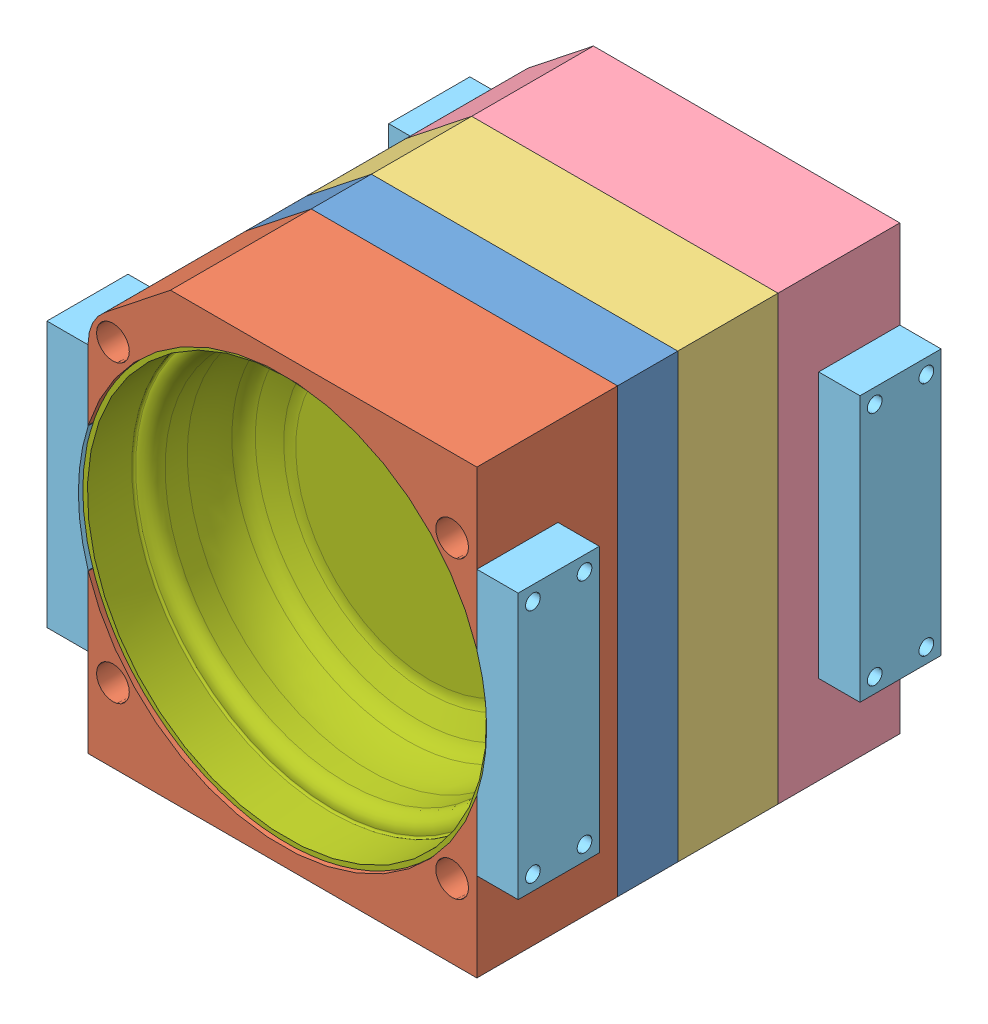
SolidWorks assembly A_FINAL_MOLD_ASSEMBLY, configuration Default. Lengths in mm.
Overall size (319.52 300 286.77).
22 component instances, 9 part files, 54 mates.
Components (placement in the parent):
- P_MOLD_SECTION_2-1: P_MOLD_SECTION_2 [Default] at (131.7625 -150 -170.9475) x (0 1 0) z (0 0 1) size (300 263.53 40.81)
- P_MOLD_SECTION_1-1: P_MOLD_SECTION_1 [Default] at (131.7625 -150 -170.9475) x (0 1 0) z (0 0 1) size (300 263.54 95.41)
- P_MOLD_SECTION_3-2: P_MOLD_SECTION_3 [Default] at (131.7625 -150 -170.9475) x (0 1 0) z (0 0 1) size (300 263.53 67.99)
- P_MOLD_SECTION_4-1: P_MOLD_SECTION_4 [Default] at (131.7625 -150 -170.9475) x (0 1 0) z (0 0 1) size (300 273.93 82.55)
- P_MOLD_SECTION_5-1: P_MOLD_SECTION_5 [Default] at (131.7625 -150 -170.9475) x (0 1 0) z (0 0 1) size (180 32.83 55)
- P_MOLD_SECTION_5-2: P_MOLD_SECTION_5 [Default] at (-131.7625 150 -170.9475) x (0 -1 0) z (0 0 1) size (180 32.83 55)
- P_MOLD_SECTION_5-3: P_MOLD_SECTION_5 [Default] at (-131.7625 -150 115.818) x (0 1 0) z (0 0 -1) size (180 32.83 55)
- P_MOLD_SECTION_5-4: P_MOLD_SECTION_5 [Default] at (131.7625 150 115.818) x (0 -1 0) z (0 0 -1) size (180 32.83 55)
- CARBON WHEEL INSIDE SHELL (FOR MOLD) R3.0-1: CARBON WHEEL INSIDE SHELL (FOR MOLD) R3.0 [Default] at (0 0 -25.5473) x (-1 0 0) z (0 1 0) size (276.85 155.45 276.85)
- CARBON WHEEL OUTSIDE SHELL (FOR MOLD) R3.0-1: CARBON WHEEL OUTSIDE SHELL (FOR MOLD) R3.0 [Default] at (0 0 -0.5473) x (1 0 0) z (0 -1 0) size (277.11 100.32 277.11)
- 1126356-Fastenal-02-08-2019.stp-1: 1126356-Fastenal-02-08-2019.stp [Default] at (-115 100 -73.3975) x (0 0 1) z (-0.923728 -0.383049 0) size (87.3 19.05 19.05)
- 1126358-Fastenal-02-08-2019.stp-1: 1126358-Fastenal-02-08-2019.stp [Default] at (-115 100 85.818) x (0 0 -1) z (1 0 0) size (100 19.05 19.05)
- 1126356-Fastenal-02-08-2019.stp-2: 1126356-Fastenal-02-08-2019.stp [Default] at (115 -100 -73.3975) x (0 0 1) z (-0.923728 -0.383049 0) size (87.3 19.05 19.05)
- 1126356-Fastenal-02-08-2019.stp-3: 1126356-Fastenal-02-08-2019.stp [Default] at (-115 -100 -73.3975) x (0 0 1) z (-0.923728 -0.383049 0) size (87.3 19.05 19.05)
- 1126356-Fastenal-02-08-2019.stp-4: 1126356-Fastenal-02-08-2019.stp [Default] at (115 100 -73.3975) x (0 0 1) z (-0.923728 -0.383049 0) size (87.3 19.05 19.05)
- 1126358-Fastenal-02-08-2019.stp-2: 1126358-Fastenal-02-08-2019.stp [Default] at (115 100 85.818) x (0 0 -1) z (1 0 0) size (100 19.05 19.05)
- 1126358-Fastenal-02-08-2019.stp-3: 1126358-Fastenal-02-08-2019.stp [Default] at (-86.25 125 -145.9475) x (0 0 1) z (-0.923728 -0.383049 0) size (100 19.05 19.05)
- 1126358-Fastenal-02-08-2019.stp-4: 1126358-Fastenal-02-08-2019.stp [Default] at (86.25 125 -145.9475) x (0 0 1) z (-0.923728 -0.383049 0) size (100 19.05 19.05)
- 1126358-Fastenal-02-08-2019.stp-5: 1126358-Fastenal-02-08-2019.stp [Default] at (86.25 -125 -145.9475) x (0 0 1) z (-0.923728 -0.383049 0) size (100 19.05 19.05)
- 1126358-Fastenal-02-08-2019.stp-6: 1126358-Fastenal-02-08-2019.stp [Default] at (-86.25 -125 -145.9475) x (0 0 1) z (-0.923728 -0.383049 0) size (100 19.05 19.05)
- 1126358-Fastenal-02-08-2019.stp-7: 1126358-Fastenal-02-08-2019.stp [Default] at (115 -100 85.818) x (0 0 -1) z (1 0 0) size (100 19.05 19.05)
- 1126358-Fastenal-02-08-2019.stp-8: 1126358-Fastenal-02-08-2019.stp [Default] at (-115 -100 85.818) x (0 0 -1) z (1 0 0) size (100 19.05 19.05)
Mates (geometry in assembly coordinates):
- Coincident1: coincident: point of ?
- Coincident2: coincident: plane of P_MOLD_SECTION_2-1 through (131.7625 -150 20.4052) normal (0 0 1); plane of ? through (131.7625 -150 20.4052) normal (0 0 -1)
- Coincident3: coincident: plane of P_MOLD_SECTION_2-1 through (-131.7625 -150 115.818) normal (0 -1 0); plane of ? through (131.7625 -150 -115.818) normal (0 -1 0)
- Coincident4: coincident: plane of P_MOLD_SECTION_2-1 through (131.7625 -150 115.818) normal (1 0 0); plane of ? through (131.7625 113.525 -115.818) normal (1 0 0)
- Coincident5: coincident: plane of P_MOLD_SECTION_2-1 through (131.7625 -150 20.4052) normal (0 0 1); plane of P_MOLD_SECTION_1-1 through (131.7625 -150 20.4052) normal (0 0 -1)
- Coincident6: coincident: plane of P_MOLD_SECTION_2-1 through (-131.7625 -150 115.818) normal (0 -1 0); plane of P_MOLD_SECTION_1-1 through (-131.7625 -150 115.818) normal (0 -1 0)
- Coincident7: coincident: plane of P_MOLD_SECTION_2-1 through (-131.7625 -150 -170.9475) normal (-1 0 0); plane of P_MOLD_SECTION_1-1 through (-131.7625 -150 -170.9475) normal (-1 0 0)
- Coincident8: coincident: plane of P_MOLD_SECTION_2-1 through (131.7625 -150 -20.4052) normal (0 0 -1); plane of P_MOLD_SECTION_3-2 through (131.7625 -150 -20.4052) normal (0 0 1)
- Coincident9: coincident: plane of P_MOLD_SECTION_2-1 through (-131.7625 -150 115.818) normal (0 -1 0); plane of P_MOLD_SECTION_3-2 through (-131.7625 -150 115.818) normal (0 -1 0)
- Coincident10: coincident: plane of P_MOLD_SECTION_2-1 through (-131.7625 -150 -170.9475) normal (-1 0 0); plane of P_MOLD_SECTION_3-2 through (-131.7625 -150 -170.9475) normal (-1 0 0)
- Coincident11: coincident: plane of P_MOLD_SECTION_3-2 through (131.7625 -150 -88.3975) normal (0 0 -1); plane of P_MOLD_SECTION_4-1 through (131.7625 -150 -88.3975) normal (0 0 1)
- Coincident12: coincident: plane of P_MOLD_SECTION_3-2 through (-131.7625 -150 115.818) normal (0 -1 0); plane of P_MOLD_SECTION_4-1 through (-131.7625 -150 115.818) normal (0 -1 0)
- Coincident13: coincident: plane of P_MOLD_SECTION_3-2 through (-131.7625 -150 -170.9475) normal (-1 0 0); plane of P_MOLD_SECTION_4-1 through (-131.7625 -150 -170.9475) normal (-1 0 0)
- Coincident14: coincident: cone of P_MOLD_SECTION_3-2 through (0 0 -31.0412) axis (0 0 1); cone of CARBON WHEEL INSIDE SHELL (FOR MOLD) R3.0-1 through (0 0 -31.0412) axis (0 0 1)
- Lock1: lock: unknown of P_MOLD_SECTION_2-1; unknown of CARBON WHEEL INSIDE SHELL (FOR MOLD) R3.0-1
- Concentric1: concentric: cylinder of P_MOLD_SECTION_1-1 through (0 0 54.4527) axis (0 0 1) radius 126.6825; cylinder of CARBON WHEEL OUTSIDE SHELL (FOR MOLD) R3.0-1 through (0 0 54.4527) axis (0 0 -1) radius 126.6825
- Coincident15: coincident: plane of P_MOLD_SECTION_2-1 through (0 0 12.5) normal (0 0 1); plane of CARBON WHEEL OUTSIDE SHELL (FOR MOLD) R3.0-1 through (0 -91.186 12.5) normal (0 0 -1)
- Lock2: lock: unknown of P_MOLD_SECTION_2-1; unknown of CARBON WHEEL OUTSIDE SHELL (FOR MOLD) R3.0-1
- Concentric2: concentric: cylinder of CARBON WHEEL INSIDE SHELL (FOR MOLD) R3.0-1 through (0 0 29.4527) axis (0 0 -1) radius 138.4275; cylinder of P_MOLD_SECTION_5-1 through (0 0 29.4527) axis (0 0 1) radius 138.4275
- Coincident16: coincident: plane of P_MOLD_SECTION_4-1 through (-101.7625 91.2533 -170.9475) normal (0 0 -1); plane of P_MOLD_SECTION_5-1 through (-101.7625 91.2533 -170.9475) normal (0 0 -1)
- Parallel1: parallel: plane of P_MOLD_SECTION_4-1 through (-131.7625 -150 -170.9475) normal (-1 0 0); plane of P_MOLD_SECTION_5-1 through (-159.7625 -150 -170.9475) normal (-1 0 0)
- Concentric3: concentric: cylinder of CARBON WHEEL INSIDE SHELL (FOR MOLD) R3.0-1 through (0 0 29.4527) axis (0 0 -1) radius 138.4275; cylinder of P_MOLD_SECTION_5-2 through (0 0 29.4527) axis (0 0 1) radius 138.4275
- Coincident19: coincident: plane of P_MOLD_SECTION_4-1 through (-101.7625 91.2533 -170.9475) normal (0 0 -1); plane of P_MOLD_SECTION_5-2 through (101.7625 -91.2533 -170.9475) normal (0 0 -1)
- Parallel2: parallel: plane of P_MOLD_SECTION_4-1 through (131.7625 -150 115.818) normal (1 0 0); plane of P_MOLD_SECTION_5-2 through (159.7625 150 -170.9475) normal (1 0 0)
- Concentric4: concentric: cylinder of CARBON WHEEL OUTSIDE SHELL (FOR MOLD) R3.0-1 through (0 0 54.4527) axis (0 0 -1) radius 138.5553; cylinder of P_MOLD_SECTION_5-3 through (0 0 -84.5822) axis (0 0 -1) radius 138.4275
- Coincident21: coincident: plane of P_MOLD_SECTION_1-1 through (-101.7625 91.2533 115.818) normal (0 0 1); plane of P_MOLD_SECTION_5-3 through (101.7625 91.2533 115.818) normal (0 0 1)
- Parallel3: parallel: plane of P_MOLD_SECTION_1-1 through (131.7625 -150 115.818) normal (1 0 0); plane of P_MOLD_SECTION_5-3 through (159.7625 -150 115.818) normal (1 0 0)
- Concentric5: concentric: cylinder of CARBON WHEEL OUTSIDE SHELL (FOR MOLD) R3.0-1 through (0 0 54.4527) axis (0 0 -1) radius 138.5553; cylinder of P_MOLD_SECTION_5-4 through (0 0 -84.5822) axis (0 0 -1) radius 138.4275
- Coincident23: coincident: plane of P_MOLD_SECTION_1-1 through (-101.7625 91.2533 115.818) normal (0 0 1); plane of P_MOLD_SECTION_5-4 through (-101.7625 -91.2533 115.818) normal (0 0 1)
- Parallel4: parallel: plane of P_MOLD_SECTION_1-1 through (-131.7625 -150 -170.9475) normal (-1 0 0); plane of P_MOLD_SECTION_5-4 through (-159.7625 150 115.818) normal (-1 0 0)
- Concentric6: concentric: cylinder of P_MOLD_SECTION_1-1 through (-115 100 2.4447) axis (0 0 1) radius 6.35; cylinder of 1126358-Fastenal-02-08-2019.stp-1 through (-115 100 46.5369) axis (0 0 -1) radius 6.35
- Coincident24: coincident: plane of P_MOLD_SECTION_1-1 through (-115 100 85.818) normal (0 0 1); plane of 1126358-Fastenal-02-08-2019.stp-1 through (-110.2375 100 85.818) normal (0 0 -1)
- Concentric7: concentric: cylinder of P_MOLD_SECTION_1-1 through (-115 -100 2.4447) axis (0 0 1) radius 6.35; cylinder of 1126358-Fastenal-02-08-2019.stp-8 through (-115 -100 46.5369) axis (0 0 -1) radius 6.35
- Coincident25: coincident: plane of P_MOLD_SECTION_1-1 through (-115 -100 85.818) normal (0 0 1); plane of 1126358-Fastenal-02-08-2019.stp-8 through (-110.2375 -100 85.818) normal (0 0 -1)
- Concentric8: concentric: cylinder of P_MOLD_SECTION_1-1 through (115 100 2.4447) axis (0 0 1) radius 6.35; cylinder of 1126358-Fastenal-02-08-2019.stp-2 through (115 100 46.5369) axis (0 0 -1) radius 6.35
- Coincident26: coincident: plane of P_MOLD_SECTION_1-1 through (115 100 85.818) normal (0 0 1); plane of 1126358-Fastenal-02-08-2019.stp-2 through (119.7625 100 85.818) normal (0 0 -1)
- Concentric9: concentric: cylinder of P_MOLD_SECTION_1-1 through (115 -100 2.4447) axis (0 0 1) radius 6.35; cylinder of 1126358-Fastenal-02-08-2019.stp-7 through (115 -100 46.5369) axis (0 0 -1) radius 6.35
- Coincident27: coincident: plane of P_MOLD_SECTION_1-1 through (115 -100 85.818) normal (0 0 1); plane of 1126358-Fastenal-02-08-2019.stp-7 through (119.7625 -100 85.818) normal (0 0 -1)
- Concentric10: concentric: cylinder of P_MOLD_SECTION_4-1 through (-86.25 -125 -70.437) axis (0 0 -1) radius 6.35; cylinder of 1126358-Fastenal-02-08-2019.stp-6 through (-86.25 -125 -106.6664) axis (0 0 1) radius 6.35
- Coincident28: coincident: circle of P_MOLD_SECTION_4-1; plane of 1126358-Fastenal-02-08-2019.stp-6 through (-90.6493 -126.8243 -145.9475) normal (0 0 1)
- Concentric11: concentric: cylinder of P_MOLD_SECTION_4-1 through (86.25 -125 -70.437) axis (0 0 -1) radius 6.35; cylinder of 1126358-Fastenal-02-08-2019.stp-5 through (86.25 -125 -106.6664) axis (0 0 1) radius 6.35
- Coincident29: coincident: circle of P_MOLD_SECTION_4-1; plane of 1126358-Fastenal-02-08-2019.stp-5 through (81.8507 -126.8243 -145.9475) normal (0 0 1)
- Concentric12: concentric: cylinder of P_MOLD_SECTION_4-1 through (-86.25 125 -70.437) axis (0 0 -1) radius 6.35; cylinder of 1126358-Fastenal-02-08-2019.stp-3 through (-86.25 125 -106.6664) axis (0 0 1) radius 6.35
- Coincident30: coincident: plane of P_MOLD_SECTION_4-1 through (-86.25 125 -145.9475) normal (0 0 -1); plane of 1126358-Fastenal-02-08-2019.stp-3 through (-90.6493 123.1757 -145.9475) normal (0 0 1)
- Concentric13: concentric: cylinder of P_MOLD_SECTION_4-1 through (86.25 125 -70.437) axis (0 0 -1) radius 6.35; cylinder of 1126358-Fastenal-02-08-2019.stp-4 through (86.25 125 -106.6664) axis (0 0 1) radius 6.35
- Coincident31: coincident: circle of P_MOLD_SECTION_4-1; plane of 1126358-Fastenal-02-08-2019.stp-4 through (81.8507 123.1757 -145.9475) normal (0 0 1)
- Concentric14: concentric: cylinder of P_MOLD_SECTION_3-2 through (115 100 -13.3975) axis (0 0 -1) radius 6.35; cylinder of 1126356-Fastenal-02-08-2019.stp-4 through (115 100 -40.4664) axis (0 0 1) radius 6.35
- Coincident32: coincident: circle of P_MOLD_SECTION_3-2; plane of 1126356-Fastenal-02-08-2019.stp-4 through (110.6007 98.1757 -73.3975) normal (0 0 1)
- Concentric15: concentric: cylinder of P_MOLD_SECTION_3-2 through (-115 -100 -13.3975) axis (0 0 -1) radius 6.35; cylinder of 1126356-Fastenal-02-08-2019.stp-3 through (-115 -100 -40.4664) axis (0 0 1) radius 6.35
- Coincident34: coincident: circle of P_MOLD_SECTION_3-2; plane of 1126356-Fastenal-02-08-2019.stp-3 through (-119.3993 -101.8243 -73.3975) normal (0 0 1)
- Concentric16: concentric: cylinder of P_MOLD_SECTION_3-2 through (-115 100 -13.3975) axis (0 0 -1) radius 6.35; cylinder of 1126356-Fastenal-02-08-2019.stp-1 through (-115 100 -40.4664) axis (0 0 1) radius 6.35
- Coincident35: coincident: plane of P_MOLD_SECTION_3-2 through (-115 100 -73.3975) normal (0 0 -1); plane of 1126356-Fastenal-02-08-2019.stp-1 through (-119.3993 98.1757 -73.3975) normal (0 0 1)
- Concentric17: concentric: cylinder of P_MOLD_SECTION_3-2 through (115 -100 -13.3975) axis (0 0 -1) radius 6.35; cylinder of 1126356-Fastenal-02-08-2019.stp-2 through (115 -100 -40.4664) axis (0 0 1) radius 6.35
- Coincident36: coincident: plane of P_MOLD_SECTION_3-2 through (115 -100 -73.3975) normal (0 0 -1); plane of 1126356-Fastenal-02-08-2019.stp-2 through (110.6007 -101.8243 -73.3975) normal (0 0 1)
